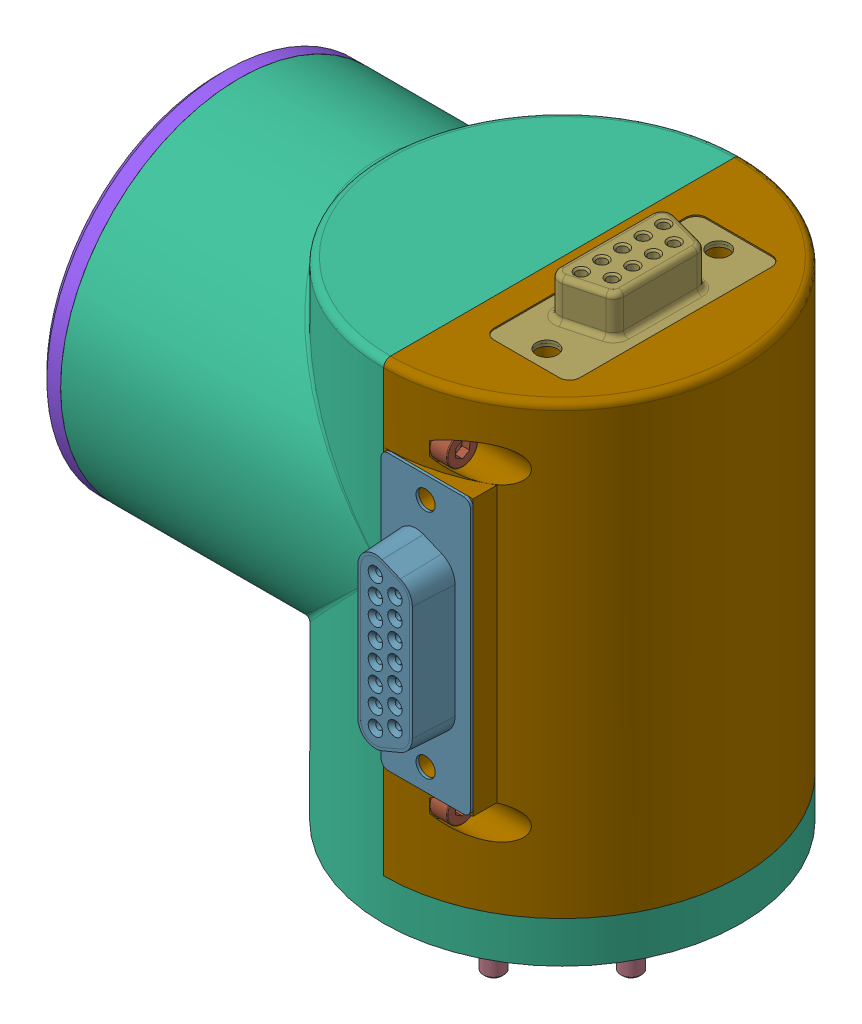
SolidWorks assembly link_1, configuration 00. Lengths in mm.
Overall size (79 90.5 58.36).
38 component instances, 16 part files, 45 mates.
Components (placement in the parent):
- shaft_1-1: shaft_1 [00] at (-48.6423 -27 0) x (1 0 0) z (0 0.707107 0.707107) size (31 32 32)
- servo_flange-1: servo_flange [По умолчанию] at (-51.1423 -27 0) x (0 1 0) z (0 0 -1) size (20 4.5 20)
- bearing_6905-2RS-1: bearing_6905-2RS [00] at (-73.6423 -27 0) size (9 42 42)
- bearing_6905-2RS-2: bearing_6905-2RS [00] at (-61.6423 -27 0) size (9 42 42)
- sleave_external_1-1: sleave_external_1 [00] at (-64.6423 -27 0) size (3 42 42)
- sleave_internal_1-1: sleave_internal_1 [00] at (-64.6423 -27 0) size (3 29 29)
- case_1-1: case_1 [По умолчанию] at (-26.6423 -71 0) x (0 0 -1) z (1 0 0) size (52 71.51 73)
- servo_MG995-1: servo_MG995 [По умолчанию] at (-6.1423 -37 0) x (0 1 0) z (-1 0 0) size (55.5 20 44.57)
- bearing_cover_1-1: bearing_cover_1 [00] at (-76.6423 -27 0) x (1 0 0) z (0 -1 0) size (3.19 52 52)
- case_cover_1-2: case_cover_1 [По умолчанию] at (-26.6423 -65 0) x (0 0 -1) z (1 0 0) size (52 65 27.19)
- slotted countersunk flat head screw_iso-39: slotted countersunk flat head screw_iso [ISO 2009 - M2 x 8 - 8N] at (-76.6423 -27 23) x (1 0 0) z (0 -0.076481 0.997071) size (8 3.8 3.77)
- slotted countersunk flat head screw_iso-40: slotted countersunk flat head screw_iso [ISO 2009 - M2 x 8 - 8N] at (-76.6423 -43.2635 16.2635) x (1 0 0) z (0 -0.759116 0.650956) size (8 3.8 3.77)
- slotted countersunk flat head screw_iso-41: slotted countersunk flat head screw_iso [ISO 2009 - M2 x 8 - 8N] at (-76.6423 -50 0) x (1 0 0) z (0 -0.997071 -0.076481) size (8 3.8 3.77)
- slotted countersunk flat head screw_iso-42: slotted countersunk flat head screw_iso [ISO 2009 - M2 x 8 - 8N] at (-76.6423 -43.2635 -16.2635) x (1 0 0) z (0 -0.650956 -0.759116) size (8 3.8 3.77)
- slotted countersunk flat head screw_iso-43: slotted countersunk flat head screw_iso [ISO 2009 - M2 x 8 - 8N] at (-76.6423 -27 -23) x (1 0 0) z (0 0.076481 -0.997071) size (8 3.8 3.77)
- slotted countersunk flat head screw_iso-44: slotted countersunk flat head screw_iso [ISO 2009 - M2 x 8 - 8N] at (-76.6423 -10.7365 -16.2635) x (1 0 0) z (0 0.759116 -0.650956) size (8 3.8 3.77)
- slotted countersunk flat head screw_iso-45: slotted countersunk flat head screw_iso [ISO 2009 - M2 x 8 - 8N] at (-76.6423 -4 0) x (1 0 0) z (0 0.997071 0.076481) size (8 3.8 3.77)
- slotted countersunk flat head screw_iso-46: slotted countersunk flat head screw_iso [ISO 2009 - M2 x 8 - 8N] at (-76.6423 -10.7365 16.2635) x (1 0 0) z (0 0.650956 0.759116) size (8 3.8 3.77)
- socket head cap screw_iso-25: socket head cap screw_iso [ISO 4762 M2.5 x 10 - 10N] at (-18.1423 -8.5 23) x (-1 0 0) z (0 -0.877208 -0.48011) size (12.5 4.5 4.5)
- socket head cap screw_iso-29: socket head cap screw_iso [ISO 4762 M2.5 x 10 - 10N] at (-18.1423 -53.5 23) x (-1 0 0) z (0 -0.877208 -0.48011) size (12.5 4.5 4.5)
- socket head cap screw_iso-27: socket head cap screw_iso [ISO 4762 M2.5 x 10 - 10N] at (-18.1423 -8.5 -23) x (-1 0 0) z (0 -0.877208 -0.48011) size (12.5 4.5 4.5)
- socket head cap screw_iso-28: socket head cap screw_iso [ISO 4762 M2.5 x 10 - 10N] at (-18.1423 -53.5 -23) x (-1 0 0) z (0 -0.877208 -0.48011) size (12.5 4.5 4.5)
- socket head cap screw_iso-20: socket head cap screw_iso [ISO 4762 M3 x 8 - 8N] at (-30.1423 -13 5) x (-1 0 0) z (0 0.270929 0.962599) size (11 5.5 5.5)
- socket head cap screw_iso-24: socket head cap screw_iso [ISO 4762 M3 x 8 - 8N] at (-30.1423 -61 5) x (-1 0 0) z (0 0.270929 0.962599) size (11 5.5 5.5)
- socket head cap screw_iso-22: socket head cap screw_iso [ISO 4762 M3 x 8 - 8N] at (-30.1423 -13 -5) x (-1 0 0) z (0 0.270929 0.962599) size (11 5.5 5.5)
- socket head cap screw_iso-23: socket head cap screw_iso [ISO 4762 M3 x 8 - 8N] at (-30.1423 -61 -5) x (-1 0 0) z (0 0.270929 0.962599) size (11 5.5 5.5)
- socket head cap screw_iso-4: socket head cap screw_iso [ISO 4762 M3 x 8 - 8N] at (-45.6423 -27 7) x (-1 0 0) z (0 0.294157 -0.955757) size (11 5.5 5.5)
- socket head cap screw_iso-5: socket head cap screw_iso [ISO 4762 M3 x 8 - 8N] at (-45.6423 -34 0) x (-1 0 0) z (0 0.955757 0.294157) size (11 5.5 5.5)
- socket head cap screw_iso-6: socket head cap screw_iso [ISO 4762 M3 x 8 - 8N] at (-45.6423 -27 -7) x (-1 0 0) z (0 -0.294157 0.955757) size (11 5.5 5.5)
- socket head cap screw_iso-7: socket head cap screw_iso [ISO 4762 M3 x 8 - 8N] at (-45.6423 -20 0) x (-1 0 0) z (0 -0.955757 -0.294157) size (11 5.5 5.5)
- circlip for shafts normal_din-1: circlip for shafts normal_din [Circlip DIN 471 - 25 x 1.2] at (-53.1423 -27 0) x (0 0 -1) z (-1 0 0) size (28.33 31.3 1.2) (hidden)
- A_DB9-1: A_DB9 [По умолчанию] at (0.3425 -22.1766 9.0281) x (0 0 -1) z (0 1 0) size (30.9 12.5 15.5)
- socket countersunk head screw_din-1: socket countersunk head screw_din [DIN 7991 - M3 x 20 --- 16.8N] at (-16.6423 -65 0) x (0 -1 0) z (-0.98859 0 0.150633) size (20 5.7 5.7)
- socket countersunk head screw_din-6: socket countersunk head screw_din [DIN 7991 - M3 x 20 --- 16.8N] at (-26.6423 -65 -10) x (0 -1 0) z (0.150633 0 0.98859) size (20 5.7 5.7)
- socket countersunk head screw_din-3: socket countersunk head screw_din [DIN 7991 - M3 x 20 --- 16.8N] at (-36.6423 -65 0) x (0 -1 0) z (0.98859 0 -0.150633) size (20 5.7 5.7)
- socket countersunk head screw_din-4: socket countersunk head screw_din [DIN 7991 - M3 x 20 --- 16.8N] at (-26.6423 -65 10) x (0 -1 0) z (-0.150633 0 -0.98859) size (20 5.7 5.7)
- DB15_F-1: DB15_F [По умолчанию] at (-21.5423 -40.695 32.31) x (0 1 0) z (1 0 0) size (40 15.72 13)
- провода^link_1-1: провода^link_1 [По умолчанию] at origin size (23.78 38.41 28.01) (virtual)
Mates (geometry in assembly coordinates):
- Концентричный2: concentric anti-aligned: cylinder of shaft_1-1 through (-48.6423 -27 0) axis (1 0 0) radius 10; cylinder of servo_flange-1 through (-48.6423 -27 0) axis (-1 0 0) radius 2.95
- Совпадение1: coincident anti-aligned: plane of shaft_1-1 through (-51.1423 -19.9289 -7.0711) normal (1 0 0); plane of servo_flange-1 through (-51.1423 -27 0) normal (-1 0 0)
- Концентричный3: concentric aligned: cylinder of shaft_1-1 through (-48.6423 -27 0) axis (-1 0 0) radius 12.5; cylinder of bearing_6905-2RS-1 through (-73.6423 -27 0) axis (-1 0 0) radius 12.5
- Совпадение2: coincident anti-aligned: plane of shaft_1-1 through (-73.6423 -18.1612 -8.8388) normal (1 0 0); plane of bearing_6905-2RS-1 through (-73.6423 -11.95 0) normal (-1 0 0)
- Концентричный4: concentric aligned: cylinder of shaft_1-1 through (-48.6423 -27 0) axis (-1 0 0) radius 12.5; cylinder of sleave_internal_1-1 through (-64.6423 -27 0) axis (-1 0 0) radius 12.5
- Совпадение3: coincident aligned: circle of bearing_6905-2RS-1; plane of sleave_internal_1-1 through (-64.6423 -12.5 0) normal (-1 0 0)
- Совпадение4: coincident anti-aligned: plane of bearing_6905-2RS-1 through (-64.6423 -8.55 0) normal (1 0 0); circle of sleave_external_1-1
- Концентричный5: concentric aligned: cylinder of shaft_1-1 through (-48.6423 -27 0) axis (-1 0 0) radius 12.5; cylinder of sleave_external_1-1 through (-64.6423 -27 0) axis (-1 0 0) radius 19
- Концентричный6: concentric aligned: cylinder of shaft_1-1 through (-48.6423 -27 0) axis (-1 0 0) radius 12.5; cylinder of bearing_6905-2RS-2 through (-61.6423 -27 0) axis (-1 0 0) radius 12.5
- Совпадение5: coincident anti-aligned: plane of bearing_6905-2RS-2 through (-61.6423 -11.95 0) normal (-1 0 0); plane of sleave_internal_1-1 through (-61.6423 -14.5 0) normal (1 0 0)
- Совпадение6: coincident anti-aligned: plane of bearing_6905-2RS-2 through (-52.6423 -8.55 0) normal (1 0 0); plane of case_1-1 through (-52.6423 -71 0) normal (-1 0 0)
- Концентричный9: concentric anti-aligned: cylinder of servo_flange-1 through (-48.6423 -27 0) axis (-1 0 0) radius 2.95; cylinder of servo_MG995-1 through (-46.9423 -27 0) axis (1 0 0) radius 2
- Параллельность2: parallel aligned: line of case_1-1 through (-26.6423 -65 26) axis (0 1 0); line of servo_MG995-1 through (-41.8423 -56.5 10) axis (0 1 0)
- Расстояние1: distance = 1 mm anti-aligned: plane of servo_MG995-1 through (-45.6423 -31.8576 4.8576) normal (-1 0 0); plane of servo_flange-1 through (-46.6423 -27 0) normal (1 0 0)
- Концентричный10: concentric anti-aligned: cylinder of case_1-1 through (-73.6423 -27 0) axis (1 0 0) radius 26; cylinder of bearing_cover_1-1 through (-76.6423 -27 0) axis (-1 0 0) radius 19
- Совпадение10: coincident anti-aligned: plane of case_1-1 through (-73.6423 -27 0) normal (-1 0 0); plane of bearing_cover_1-1 through (-73.6423 -27 26) normal (1 0 0)
- Концентричный12: concentric aligned: circle of case_1-1; cylinder of bearing_cover_1-1 through (-76.6423 -27 23) axis (-1 0 0) radius 1.2
- Совпадение14: coincident anti-aligned: plane of case_1-1 through (-49.6423 -65 0) normal (0 1 0); plane of case_cover_1-2 through (-26.6423 -65 0) normal (0 -1 0)
- Совпадение15: coincident anti-aligned: plane of case_1-1 through (-26.6423 -65 26) normal (1 0 0); plane of case_cover_1-2 through (-26.6423 0 26) normal (-1 0 0)
- Совпадение16: coincident anti-aligned: line of case_1-1 through (-26.6423 -65 -26) axis (0 1 0); line of case_cover_1-2 through (-26.6423 -1 -26) axis (0 -1 0)
- Концентричный13: concentric aligned: circle of bearing_cover_1-1; cylinder of slotted countersunk flat head screw_iso-39 through (-82.9923 -27 23) axis (-1 0 0) radius 1
- Совпадение17: coincident aligned: cone of bearing_cover_1-1 through (-76.6423 -27 23) axis (1 0 0); cone of slotted countersunk flat head screw_iso-39 through (-76.3423 -27 23) axis (1 0 0)
- Концентричный14: concentric aligned: circle of case_cover_1-2; cylinder of socket head cap screw_iso-25 through (13.6077 -8.5 23) axis (1 0 0) radius 1.25
- Совпадение18: coincident anti-aligned: plane of case_cover_1-2 through (-20.6423 -8.5 23) normal (1 0 0); plane of socket head cap screw_iso-25 through (-20.6423 -7.4198 21.0263) normal (-1 0 0)
- Концентричный15: concentric aligned: cylinder of socket head cap screw_iso-20 through (1.6077 -13 5) axis (1 0 0) radius 2.75; circle of case_1-1
- Совпадение19: coincident anti-aligned: plane of servo_MG995-1 through (-33.1423 -16.7 -9.5) normal (1 0 0); plane of socket head cap screw_iso-20 through (-33.1423 -15.6471 5.7451) normal (-1 0 0)
- Концентричный18: concentric anti-aligned: cylinder of servo_flange-1 through (-48.6423 -27 7) axis (-1 0 0) radius 1.5; cylinder of socket head cap screw_iso-4 through (-13.8923 -27 7) axis (1 0 0) radius 1.5
- Совпадение22: coincident anti-aligned: plane of servo_flange-1 through (-48.6423 -27 0) normal (1 0 0); plane of socket head cap screw_iso-4 through (-48.6423 -24.3717 7.8089) normal (-1 0 0)
- Концентричный21: concentric aligned: cylinder of case_1-1 through (61.1822 76.2749 23.9927) axis (0.087096 0.551376 -0.829698) radius 1.7; cylinder of ? through (61.7353 79.7762 18.7241) axis (0.087096 0.551376 -0.829698) radius 1.5
- Совпадение23: coincident aligned: cone of case_1-1 through (61.1822 76.2749 23.9927) axis (-0.087096 -0.551376 0.829698); cone of ? through (61.1474 76.0544 24.3246) axis (-0.087096 -0.551376 0.829698)
- Концентричный22: concentric anti-aligned: cylinder of shaft_1-1 through (-48.6423 -27 0) axis (1 0 0) radius 11.8; cylinder of circlip for shafts normal_din-1 through (-51.9423 -27 0) axis (-1 0 0) radius 11.95
- Совпадение25: coincident anti-aligned: plane of shaft_1-1 through (-53.1423 -18.1612 -8.8388) normal (1 0 0); plane of circlip for shafts normal_din-1 through (-53.1423 -27 0) normal (-1 0 0)
- Симметричный1: symmetric aligned: cylinder of circlip for shafts normal_din-1 through (-51.9423 -12.664 1.6) axis (-1 0 0) radius 1; cylinder of circlip for shafts normal_din-1 through (-51.9423 -12.664 -1.6) axis (-1 0 0) radius 1; plane of assembly through (0 0 0) normal (0 0 1)
- Совпадение26: coincident anti-aligned: plane of case_cover_1-2 through (-26.6423 -1 0) normal (0 1 0); plane of A_DB9-1 through (-16.3923 -1 0) normal (0 -1 0)
- Параллельность4: parallel aligned: line of A_DB9-1 through (-10.1423 -0.2 13.95) axis (0 0 -1); line of case_cover_1-2 through (-10.1423 0 13.95) axis (0 0 -1)
- Концентричный23: concentric aligned: circle of A_DB9-1; cylinder of case_cover_1-2 through (-16.3923 -1 12.5) axis (0 1 0) radius 1.575
- Концентричный24: concentric aligned: cylinder of case_1-1 through (-16.6423 -65 0) axis (0 1 0) radius 1.7; cylinder of socket countersunk head screw_din-1 through (-16.6423 -65 0) axis (0 1 0) radius 1.5
- Совпадение27: coincident aligned: plane of case_1-1 through (-49.6423 -65 0) normal (0 1 0); plane of socket countersunk head screw_din-1 through (-16.6423 -65 0) normal (0 1 0)
- Концентричный25: concentric anti-aligned: cylinder of bearing_6905-2RS-1 through (-73.6423 -27 0) axis (-1 0 0) radius 21; cylinder of case_1-1 through (-73.6423 -27 0) axis (1 0 0) radius 21
- Концентричный26: concentric anti-aligned: cylinder of shaft_1-1 through (-51.1423 -20 0) axis (1 0 0) radius 1.25; cylinder of servo_flange-1 through (-48.6423 -20 0) axis (-1 0 0) radius 1.5
- Совпадение28: coincident aligned: plane of case_1-1 through (-52.6423 0 0) normal (0 1 0); plane of assembly through (0 0 0) normal (0 1 0)
- Совпадение29: coincident anti-aligned: plane of case_cover_1-2 through (-26.6423 -65 26) normal (0 0 1); plane of DB15_F-1 through (-14.6223 -12 26) normal (0 0 -1)
- Концентричный27: concentric anti-aligned: cylinder of case_cover_1-2 through (-20.1423 -14.18 16) axis (0 0 1) radius 1.5; circle of DB15_F-1
- Концентричный28: concentric anti-aligned: cylinder of case_cover_1-2 through (-20.1423 -47.82 16) axis (0 0 1) radius 1.5; cylinder of DB15_F-1 through (-20.1423 -47.82 32.31) axis (0 0 -1) radius 1.4
- Угол1: planar angle = 0.785398 rad aligned: plane of shaft_1-1 through (-48.6423 -27 0) normal (0 0.707107 0.707107); plane of assembly through (0 0 0) normal (0 0 1)
